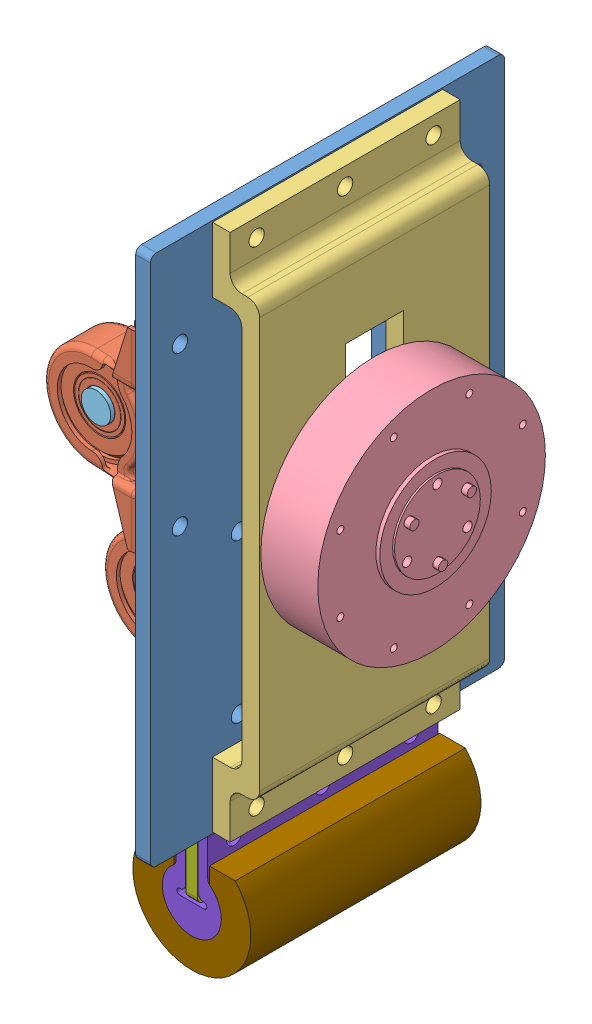
SolidWorks assembly Knuckle, configuration Default. Lengths in mm.
Overall size (99.97 283.85 152.4).
12 component instances, 9 part files, 36 mates.
Components (placement in the parent):
- Knuckle Plate^Knuckle-1: Knuckle Plate^Knuckle [Default] at origin size (6.35 228.6 152.4) (virtual)
- 5913K61_Low-Profile Mounted Sealed Steel Ball Bearing-1: 5913K61_Low-Profile Mounted Sealed Steel Ball Bearing [5913K61] at (-22.2 0 -63.5) x (0 1 0) z (0 0 1) size (86.1 44.81 28.6)
- 5913K61_Low-Profile Mounted Sealed Steel Ball Bearing-3: 5913K61_Low-Profile Mounted Sealed Steel Ball Bearing [5913K61] at (-22.2 0 63.5) x (0 -1 0) z (0 0 -1) size (86.1 44.81 28.6)
- 5913K61_Low-Profile Mounted Sealed Steel Ball Bearing-4: 5913K61_Low-Profile Mounted Sealed Steel Ball Bearing [5913K61] at (-22.2 -82.55 -38.1) x (0 1 0) z (0 0 1) size (86.1 44.81 28.6)
- 5913K61_Low-Profile Mounted Sealed Steel Ball Bearing-6: 5913K61_Low-Profile Mounted Sealed Steel Ball Bearing [5913K61] at (-22.2 -82.55 38.1) x (0 -1 0) z (0 0 -1) size (86.1 44.81 28.6)
- 00_04_01_CANSide mount-1: 00_04_01_CANSide mount [Default] at (19.05 -127 0) x (-1 0 0) z (0 0 -1) size (20.32 227.33 99.06)
- CE_AK80-6_Model-1: CE_AK80-6_Model [AliExpress (2.5mm)] at (26.67 -41.275 0) x (0 -1 0) z (0 0 1) size (98 40.5 98)
- Boom_Knuckle Shaft-1: Boom_Knuckle Shaft [Default] at (-22.2 0 0) x (0 0 -1) z (1 0 0) size (142.17 12.7 12.7)
- Rod_Knuckle Shaft-1: Rod_Knuckle Shaft [Default] at (-22.2 -82.55 0) x (0 0 -1) z (-1 0 0) size (94.55 12.7 12.7)
- Bumper^Knuckle-1: Bumper^Knuckle [Default] at (0 -147.32 0) x (0 0 1) z (-1 0 0) size (99.06 46.04 5) (virtual)
- SleeveHolder^Knuckle-1: SleeveHolder^Knuckle [Default] at (-2.5085 -185.42 0) size (25.4 41.27 99.06) (virtual)
- Sleeve^Knuckle-2: Sleeve^Knuckle [Default] at (-2.5085 -185.42 0) size (50.8 42.6 99.06) (virtual)
Mates (geometry in assembly coordinates):
- Coincident2: coordinate: point of Knuckle Plate^Knuckle-1
- Coincident3: coincident anti-aligned: plane of Knuckle Plate^Knuckle-1 through (0 0 0) normal (-1 0 0); plane of 5913K61_Low-Profile Mounted Sealed Steel Ball Bearing-1 through (0 -43 -51) normal (1 0 0)
- Coincident4: coincident aligned: plane of 5913K61_Low-Profile Mounted Sealed Steel Ball Bearing-1 through (-22.2 0 -63.5) normal (0 1 0)
- Coincident5: coincident: line of Knuckle Plate^Knuckle-1 through (0 34.0001 -63.5) axis (0 -1 0); plane of 5913K61_Low-Profile Mounted Sealed Steel Ball Bearing-1 through (-22.2 0 -63.5) normal (0 0 1)
- Coincident7: coincident anti-aligned: plane of Knuckle Plate^Knuckle-1 through (0 0 0) normal (-1 0 0); plane of 5913K61_Low-Profile Mounted Sealed Steel Ball Bearing-3 through (0 43 51) normal (1 0 0)
- Coincident8: coincident anti-aligned: plane of 5913K61_Low-Profile Mounted Sealed Steel Ball Bearing-3 through (-22.2 0 63.5) normal (0 -1 0)
- Coincident9: coincident anti-aligned: plane of Knuckle Plate^Knuckle-1 through (0 0 0) normal (-1 0 0); plane of 5913K61_Low-Profile Mounted Sealed Steel Ball Bearing-4 through (0 -125.55 -25.6) normal (1 0 0)
- Coincident11: coincident anti-aligned: plane of Knuckle Plate^Knuckle-1 through (0 -82.55 0) normal (0 -1 0); plane of 5913K61_Low-Profile Mounted Sealed Steel Ball Bearing-4 through (-22.2 -82.55 -38.1) normal (0 1 0)
- Coincident12: coincident: line of Knuckle Plate^Knuckle-1 through (0 -48.5499 -38.1) axis (0 -1 0); plane of 5913K61_Low-Profile Mounted Sealed Steel Ball Bearing-4 through (-22.2 -82.55 -38.1) normal (0 0 1)
- Coincident16: coincident: line of Knuckle Plate^Knuckle-1 through (0 34.0001 63.5) axis (0 -1 0); plane of 5913K61_Low-Profile Mounted Sealed Steel Ball Bearing-3 through (-22.2 0 63.5) normal (0 0 -1)
- Coincident17: coincident anti-aligned: plane of Knuckle Plate^Knuckle-1 through (0 0 0) normal (-1 0 0); plane of 5913K61_Low-Profile Mounted Sealed Steel Ball Bearing-6 through (0 -39.55 25.6) normal (1 0 0)
- Coincident18: coincident aligned: plane of Knuckle Plate^Knuckle-1 through (0 -82.55 0) normal (0 -1 0); plane of 5913K61_Low-Profile Mounted Sealed Steel Ball Bearing-6 through (-22.2 -82.55 38.1) normal (0 -1 0)
- Coincident19: coincident: line of Knuckle Plate^Knuckle-1 through (0 -48.5499 38.1) axis (0 -1 0); plane of 5913K61_Low-Profile Mounted Sealed Steel Ball Bearing-6 through (-22.2 -82.55 38.1) normal (0 0 -1)
- Coincident20: coincident aligned: plane of Knuckle Plate^Knuckle-1 through (0 -41.275 0) normal (0 1 0); plane of 00_04_01_CANSide mount-1 through (19.05 -41.275 0) normal (0 1 0)
- Coincident21: coincident anti-aligned: plane of Knuckle Plate^Knuckle-1 through (6.35 0 0) normal (1 0 0); plane of 00_04_01_CANSide mount-1 through (6.35 52.07 -49.53) normal (-1 0 0)
- Coincident22: coincident anti-aligned: plane of Knuckle Plate^Knuckle-1 through (0 0 0) normal (0 0 1); plane of 00_04_01_CANSide mount-1 through (19.05 -127 0) normal (0 0 -1)
- Concentric3: concentric anti-aligned: cylinder of 00_04_01_CANSide mount-1 through (134.4331 -41.275 0) axis (-1 0 0) radius 38.1; cylinder of CE_AK80-6_Model-1 through (15.67 -41.275 0) axis (1 0 0) radius 35.5
- Coincident24: coincident aligned: plane of CE_AK80-6_Model-1 through (26.67 -41.275 0) normal (0 0 1)
- Coincident25: coincident anti-aligned: plane of 00_04_01_CANSide mount-1 through (26.67 -134.62 -49.53) normal (1 0 0); plane of CE_AK80-6_Model-1 through (26.67 -41.275 0) normal (-1 0 0)
- Concentric4: concentric anti-aligned: cylinder of 5913K61_Low-Profile Mounted Sealed Steel Ball Bearing-1 through (-22.2 0 -63.5) axis (0 0 -1) radius 6.35; cylinder of Boom_Knuckle Shaft-1 through (-22.2 0 -90.6355) axis (0 0 1) radius 6.35
- Coincident27: coincident aligned: plane of Boom_Knuckle Shaft-1 through (-22.2 0 0) normal (0 1 0)
- Coincident28: coincident anti-aligned: plane of Boom_Knuckle Shaft-1 through (-22.2 0 0) normal (0 0 -1)
- Concentric5: concentric anti-aligned: cylinder of 5913K61_Low-Profile Mounted Sealed Steel Ball Bearing-4 through (-22.2 -82.55 -38.1) axis (0 0 -1) radius 6.35; cylinder of Rod_Knuckle Shaft-1 through (-22.2 -82.55 -65.2355) axis (0 0 1) radius 6.35
- Coincident29: coincident aligned: plane of Knuckle Plate^Knuckle-1 through (0 -82.55 0) normal (0 -1 0); plane of Rod_Knuckle Shaft-1 through (-22.2 -82.55 0) normal (0 -1 0)
- Coincident30: coincident anti-aligned: plane of Rod_Knuckle Shaft-1 through (-22.2 -82.55 0) normal (0 0 -1)
- Coincident34: coincident aligned: plane of Knuckle Plate^Knuckle-1 through (0 0 0) normal (0 0 1); plane of Bumper^Knuckle-1 through (0 -147.32 0) normal (0 0 1)
- Coincident35: coincident anti-aligned: plane of Knuckle Plate^Knuckle-1 through (0 0 0) normal (-1 0 0); plane of Bumper^Knuckle-1 through (0 -147.32 0) normal (1 0 0)
- Concentric6: concentric anti-aligned: cylinder of Knuckle Plate^Knuckle-1 through (6.35 -147.32 0) axis (-1 0 0) radius 3.302; cylinder of Bumper^Knuckle-1 through (-5 -147.32 0) axis (1 0 0) radius 3.302
- Coincident40: coincident anti-aligned: plane of Knuckle Plate^Knuckle-1 through (0 0 0) normal (0 0 1); plane of Bumper^Knuckle-4 through (13.97 -147.32 0) normal (0 0 -1)
- Coincident41: coincident anti-aligned: plane of 00_04_01_CANSide mount-1 through (13.97 -154.94 -49.53) normal (1 0 0); plane of Bumper^Knuckle-4 through (13.97 -147.32 0) normal (-1 0 0)
- Concentric10: concentric aligned: cylinder of Knuckle Plate^Knuckle-1 through (6.35 -147.32 0) axis (-1 0 0) radius 3.302; cylinder of Bumper^Knuckle-4 through (20.32 -147.32 0) axis (-1 0 0) radius 3.302
- Coincident42: coincident anti-aligned: plane of Part2^Knuckle-1 through (-36.9201 -192.3946 0) normal (0 0 -1)
- Coincident43: coincident aligned: plane of Bumper^Knuckle-1 through (0 -147.32 0) normal (0 0 1); plane of SleeveHolder^Knuckle-1 through (-2.5085 -185.42 0) normal (0 0 1)
- Parallel1: parallel anti-aligned: plane of Bumper^Knuckle-1 through (0 -147.32 0) normal (-1 0 0)
- Concentric11: concentric aligned: cylinder of Bumper^Knuckle-1 through (-108.5503 -163.195 0) axis (1 0 0) radius 3.302; cylinder of SleeveHolder^Knuckle-1 through (-18.7059 -163.195 0) axis (1 0 0) radius 3.302
- Coincident44: coordinate: point of SleeveHolder^Knuckle-1; point of Sleeve^Knuckle-2
